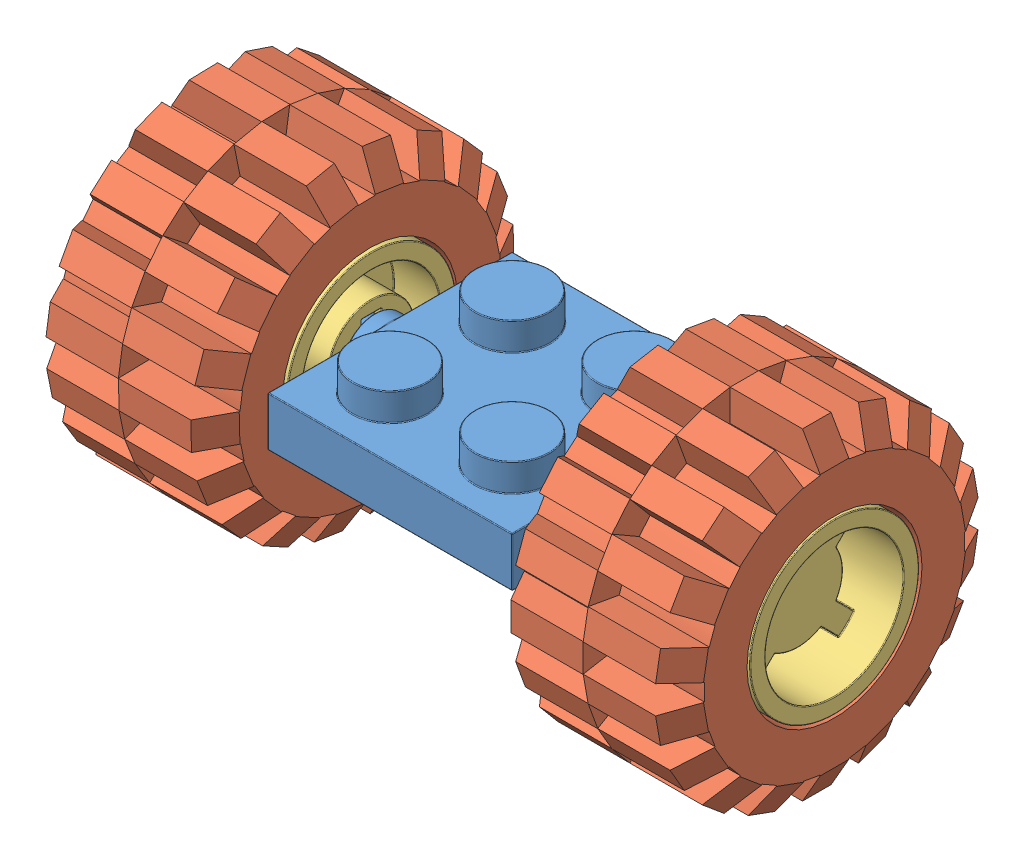
SolidWorks assembly Wheel Assembly, configuration Default. Lengths in mm.
Overall size (42 29.52 29.52).
5 component instances, 3 part files, 8 mates.
Components (placement in the parent):
- 4211504-1: 4211504 [Default] at (-7.319 -0.7451 4.3684) size (27.68 6.09 15.92)
- 4514560-1: 4514560 [Default] at (-18.469 0.3282 0.3884) x (1 0 0) z (0 -0.782052 0.623213) size (11.74 21 21)
- 4514560-2: 4514560 [Default] at (11.791 0.3282 0.3884) size (11.74 21 21)
- 4170457-1: 4170457 [Default] at (-12.499 0.3282 0.3884) x (0 1 0) z (0 0 1) size (11 11.84 11)
- 4170457-2: 4170457 [Default] at (5.821 0.3282 0.3884) x (0 -1 0) z (0 0 1) size (11 11.84 11)
Mates (geometry in assembly coordinates):
- Coincident1: coincident aligned: plane of 4170457-1 through (-24.339 0.3282 0.3884) normal (-1 0 0); plane of 4514560-1 through (-24.339 0.3282 0.3884) normal (-1 0 0)
- Coincident2: coincident aligned: plane of 4170457-2 through (17.661 0.3282 0.3884) normal (1 0 0); plane of 4514560-2 through (17.661 0.3282 0.3884) normal (1 0 0)
- Concentric1: concentric anti-aligned: cylinder of 4514560-1; cylinder of 4170457-1
- Concentric2: concentric aligned: cylinder of 4514560-2; cylinder of 4170457-2
- Concentric3: concentric anti-aligned: cylinder of 4211504-1; cylinder of 4170457-1
- Concentric4: concentric anti-aligned: cylinder of 4211504-1; cylinder of 4170457-2
- Distance1: distance = 0.2 mm anti-aligned: plane of 4170457-1 through (-12.499 0.3282 0.3884) normal (1 0 0); plane of 4211504-1 through (-12.299 0.3282 0.3884) normal (-1 0 0)
- Distance2: distance = 0.2 mm anti-aligned: plane of 4170457-2 through (5.821 0.3282 0.3884) normal (-1 0 0); plane of 4211504-1 through (5.621 0.3282 0.3884) normal (1 0 0)
